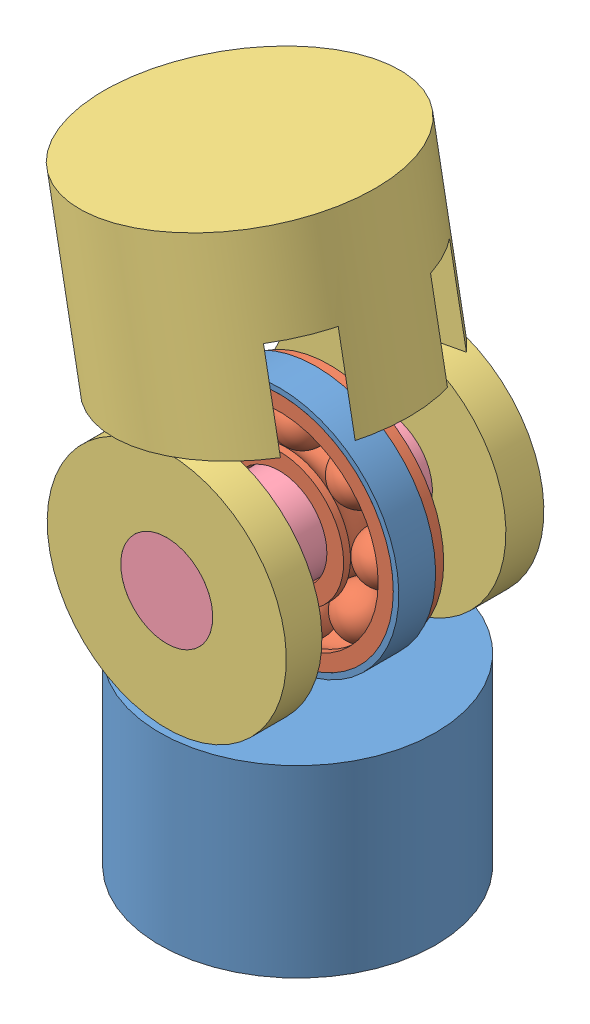
SolidWorks assembly Assem3, configuration Default. Lengths in mm.
Overall size (94.89 170.49 75.57).
4 component instances, 4 part files, 5 mates.
Components (placement in the parent):
- IOWER-1: IOWER [Default] at (16.4084 21.7131 76.824) x (-1 0 0) z (0 -1 0) size (75 75 115)
- BEARING-1: BEARING [Default] at (16.4084 79.2131 74.9696) x (0.999675 0.025504 0) z (-0.025504 0.999675 0) size (62 13.71 62)
- UPPER-1: UPPER [Default] at (5.8233 135.7304 77.3967) x (-0.98291 -0.184089 0) z (-0.184089 0.98291 0) size (75 75 115)
- Part7-1: Part7 [Default] at (16.4084 79.2131 42.3967) x (0.999913 -0.013203 0) z (0 0 1) size (25 25 70)
Mates (geometry in assembly coordinates):
- Concentric4: concentric anti-aligned: cylinder of IOWER-1 through (16.4084 79.2131 81.824) axis (0 0 -1) radius 31; cylinder of BEARING-1 through (16.4084 79.2131 82.5094) axis (0 0 1) radius 31
- Coincident1: coincident aligned: plane of IOWER-1 through (16.4084 79.2131 81.824) normal (0 0 1); plane of BEARING-1 through (-14.5815 78.4224 81.824) normal (0 0 1)
- Concentric5: concentric anti-aligned: cylinder of BEARING-1 through (16.4084 79.2131 82.5094) axis (0 0 1) radius 12.9511; cylinder of Part7-1 through (16.4084 79.2131 112.3967) axis (0 0 -1) radius 12.5
- Concentric6: concentric anti-aligned: cylinder of UPPER-1 through (16.4084 79.2131 42.3967) axis (0 0 1) radius 12.5; cylinder of Part7-1 through (16.4084 79.2131 112.3967) axis (0 0 -1) radius 12.5
- Coincident2: coincident aligned: plane of UPPER-1 through (16.4084 79.2131 112.3967) normal (0 0 1); plane of Part7-1 through (16.4084 79.2131 112.3967) normal (0 0 1)
